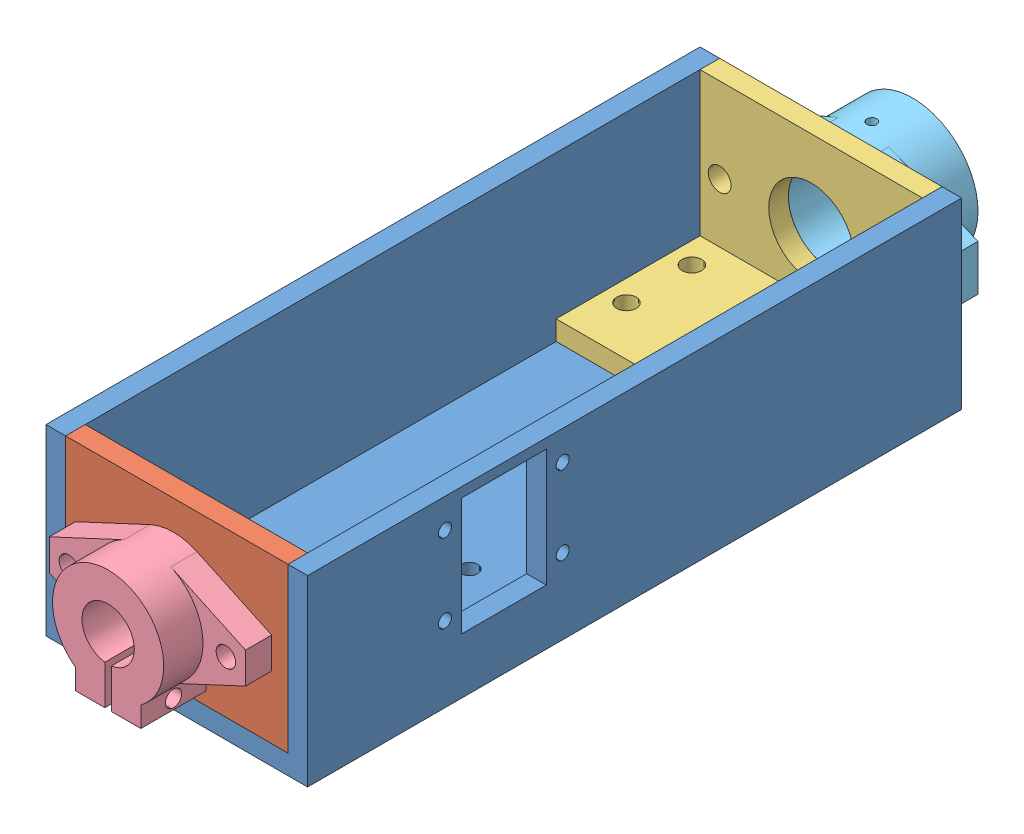
SolidWorks assembly 棘轮装配体, configuration 默认. Lengths in mm.
Overall size (80 59.24 245).
5 component instances, 5 part files, 12 mates.
Components (placement in the parent):
- 棘轮箱底板-1: 棘轮箱底板 [默认] at origin size (80 59.24 200)
- 棘轮箱端面-1: 棘轮箱端面 [默认] at (0 12 160) x (1 0 0) z (0 0 -1) size (68 50 40)
- 棘轮箱断面-25-1: 棘轮箱断面-25 [默认] at (0 12 50) x (-1 0 0) z (0 0 1) size (68 50 50)
- 棘轮箱轴承支座16-1: 棘轮箱轴承支座16 [默认] at (-1 30 200) x (0 0 1) z (1 0 0) size (20 37 60)
- 轴承支座26-1: 轴承支座26 [默认] at (0 30 0) x (1 0 0) z (0 0 -1) size (70 47.49 25)
Mates (geometry in assembly coordinates):
- 同心1: concentric anti-aligned: cylinder of 棘轮箱底板-1 through (-27.5 56.001 15) axis (0 -1 0) radius 2.5; cylinder of 棘轮箱断面-25-1 through (-27.5 6 15) axis (0 1 0) radius 3
- 同心2: concentric anti-aligned: cylinder of 棘轮箱底板-1 through (27.5 56.001 15) axis (0 -1 0) radius 2.5; cylinder of 棘轮箱断面-25-1 through (27.5 6 15) axis (0 1 0) radius 3
- 重合1: coincident anti-aligned: plane of 棘轮箱断面-25-1 through (0 6 50) normal (0 -1 0); plane of 棘轮箱底板-1 through (34 6 200) normal (0 1 0)
- 同心3: concentric anti-aligned: cylinder of 棘轮箱底板-1 through (-27.5 56.001 185) axis (0 -1 0) radius 2.5; cylinder of 棘轮箱端面-1 through (-27.5 6 185) axis (0 1 0) radius 2.5
- 同心4: concentric anti-aligned: cylinder of 棘轮箱底板-1 through (27.5 56.001 185) axis (0 -1 0) radius 2.5; cylinder of 棘轮箱端面-1 through (27.5 6 185) axis (0 1 0) radius 2.5
- 重合2: coincident anti-aligned: plane of 棘轮箱底板-1 through (34 6 200) normal (0 1 0); plane of 棘轮箱端面-1 through (0 6 160) normal (0 -1 0)
- 同心5: concentric aligned: cylinder of 棘轮箱端面-1 through (-1 30 200.001) axis (0 0 -1) radius 8; cylinder of 棘轮箱轴承支座16-1 through (-1 30 220) axis (0 0 -1) radius 8
- 同心6: concentric aligned: cylinder of 棘轮箱端面-1 through (-25 30 200.001) axis (0 0 -1) radius 3; cylinder of 棘轮箱轴承支座16-1 through (-25 30 208) axis (0 0 -1) radius 3
- 重合3: coincident anti-aligned: plane of 棘轮箱端面-1 through (-34 6 200) normal (0 0 1); plane of 棘轮箱轴承支座16-1 through (-1 30 200) normal (0 0 -1)
- 重合4: coincident anti-aligned: plane of 棘轮箱断面-25-1 through (34 6 0) normal (0 0 -1); plane of 轴承支座26-1 through (0 30 0) normal (0 0 1)
- 同心8: concentric aligned: cylinder of 棘轮箱断面-25-1 through (28 30 -0.001) axis (0 0 1) radius 3.5; cylinder of 轴承支座26-1 through (28 30 -10) axis (0 0 1) radius 3.5
- 同心15: concentric aligned: cylinder of 棘轮箱断面-25-1 through (0 30 -0.001) axis (0 0 1) radius 13; cylinder of 轴承支座26-1 through (0 30 -10) axis (0 0 1) radius 13
